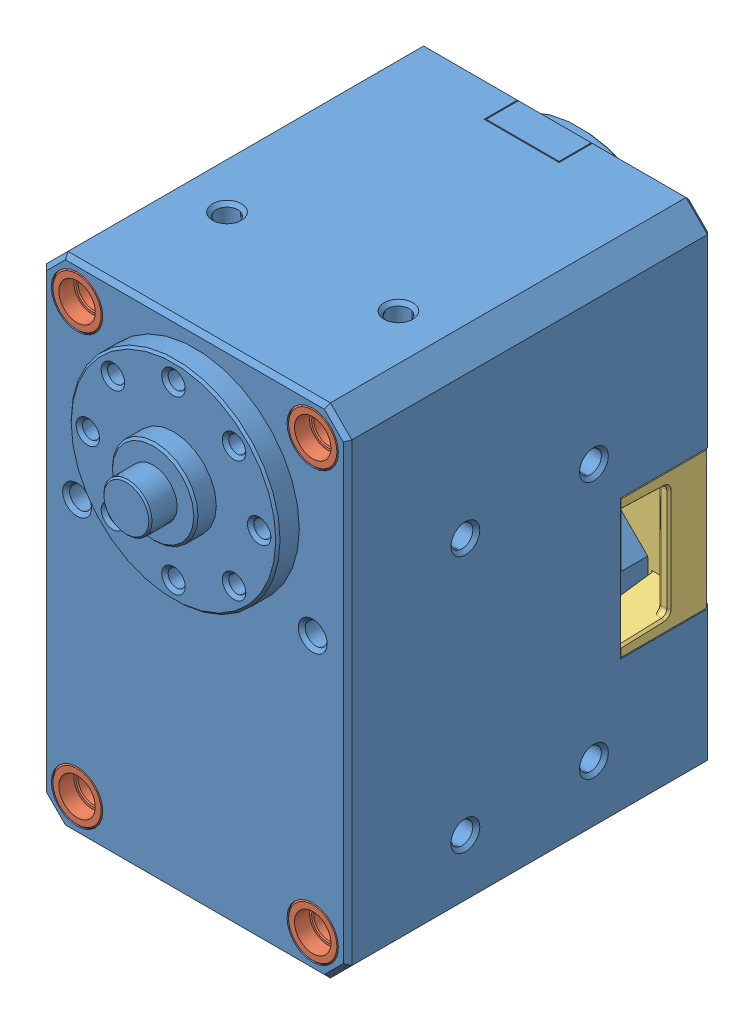
SolidWorks assembly x-430_idle, configuration 기본. Lengths in mm.
Overall size (28.5 46.5 42.4).
10 component instances, 3 part files, 0 mates.
Components (placement in the parent):
- X-430_IDLE-1: X-430_IDLE [기본] at origin size (28.5 46.5 42.4)
- X-430_SPACER_RING-1: X-430_SPACER_RING [기본] at (11 8 14.2) x (-1 0 0) z (0 1 0) size (4.8 2.8 4.8)
- X-430_SPACER_RING-2: X-430_SPACER_RING [기본] at (-11 8 14.2) x (-1 0 0) z (0 1 0) size (4.8 2.8 4.8)
- X-430_SPACER_RING-3: X-430_SPACER_RING [기본] at (11 -32 14.2) x (-1 0 0) z (0 1 0) size (4.8 2.8 4.8)
- X-430_SPACER_RING-4: X-430_SPACER_RING [기본] at (-11 -32 14.2) x (-1 0 0) z (0 1 0) size (4.8 2.8 4.8)
- X-430_SPACER_RING-5: X-430_SPACER_RING [기본] at (-11 8 -14.2) x (1 0 0) z (0 1 0) size (4.8 2.8 4.8)
- X-430_SPACER_RING-6: X-430_SPACER_RING [기본] at (11 8 -14.2) x (1 0 0) z (0 1 0) size (4.8 2.8 4.8)
- X-430_SPACER_RING-7: X-430_SPACER_RING [기본] at (-11 -32 -14.2) x (1 0 0) z (0 1 0) size (4.8 2.8 4.8)
- X-430_SPACER_RING-8: X-430_SPACER_RING [기본] at (11 -32 -14.2) x (1 0 0) z (0 1 0) size (4.8 2.8 4.8)
- X-430_CVR_CABLE-1: X-430_CVR_CABLE [기본] at origin size (28.5 12.8 8.8)
